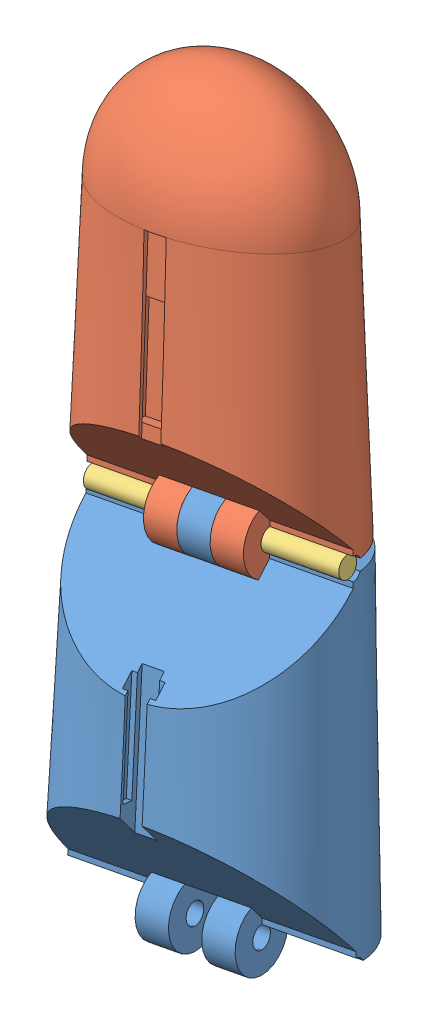
SolidWorks assembly Assem4 thumb, configuration Default. Lengths in mm.
Overall size (34.32 74.41 29.87).
3 component instances, 3 part files, 4 mates.
Components (placement in the parent):
- part 1 thumb-1: part 1 thumb [Default] at (14.5771 23.6089 32.2095) x (-0.988676 -0.093394 0.117464) z (0.102966 0.147252 0.983725) size (26.08 37 20.01)
- part 3 thumb-1: part 3 thumb [Default] at (11.8048 49.2961 29.2993) x (-0.988676 -0.093394 0.117464) z (0.105649 0.122719 0.986802) size (24.07 39.51 17.01)
- mate1 thumb-1: mate1 thumb [Default] at (3.1527 23.0272 33.4924) x (-0.018558 -0.700646 -0.713268) z (0.988676 0.093394 -0.117464) size (2 2 23)
Mates (geometry in assembly coordinates):
- Concentric1: concentric anti-aligned: cylinder of part 1 thumb-1 through (27.3816 25.3159 30.6138) axis (-0.988676 -0.093394 0.117464) radius 1; cylinder of part 3 thumb-1 through (2.6471 22.9794 33.5525) axis (0.988676 0.093394 -0.117464) radius 1
- Coincident1: coincident anti-aligned: plane of part 1 thumb-1 through (16.0055 24.2413 31.9654) normal (0.988676 0.093394 -0.117464); plane of part 3 thumb-1 through (16.0055 24.2413 31.9654) normal (-0.988676 -0.093394 0.117464)
- Concentric2: concentric anti-aligned: cylinder of part 3 thumb-1 through (2.6471 22.9794 33.5525) axis (0.988676 0.093394 -0.117464) radius 1; cylinder of mate1 thumb-1 through (25.8923 25.1752 30.7907) axis (-0.988676 -0.093394 0.117464) radius 1
- Width1: width anti-aligned: plane of mate1 thumb-1 through (3.1527 23.0272 33.4924) normal (-0.988676 -0.093394 0.117464); plane of part 3 thumb-1 through (25.8923 25.1752 30.7907) normal (0.988676 0.093394 -0.117464); plane of mate1 thumb-1 through (18.9716 24.5215 31.613) normal (0.988676 0.093394 -0.117464); plane of part 3 thumb-1 through (10.0735 23.6809 32.6701) normal (-0.988676 -0.093394 0.117464)
